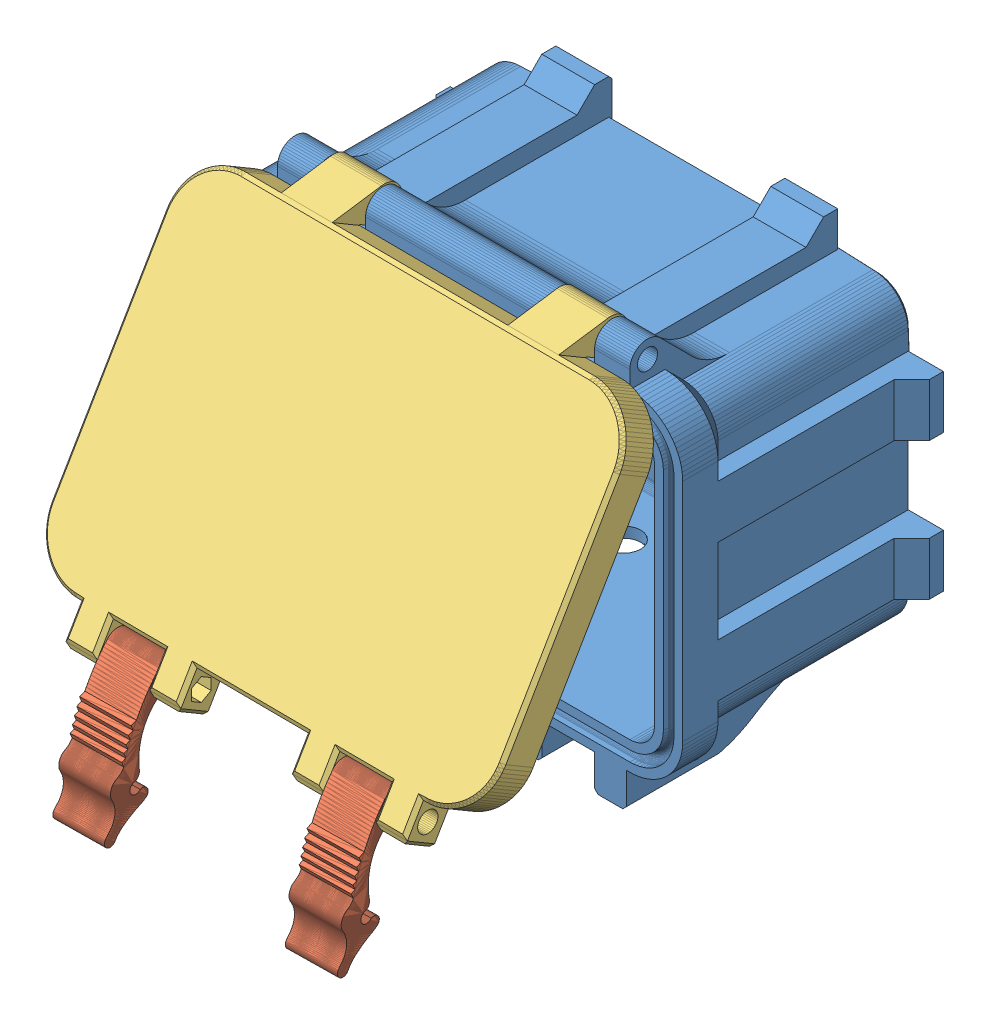
SolidWorks assembly Assem1, configuration Default. Lengths in mm.
Overall size (178.06 170.46 187.47).
4 component instances, 3 part files, 0 mates.
Components (placement in the parent):
- Enclosure-1: Enclosure [Default] at (87.724 108.5663 114.8266) size (178.06 144.98 89.03)
- Enclosure_Latch-1: Enclosure_Latch [Default] at (138.0626 22.1655 279.5419) x (-0.005073 0.943211 -0.332155) z (-0.999905 -0.000526 0.013778) size (53.78 15.23 18.57)
- LID-1: LID [Default] at (-71.5061 242.0804 171.4742) x (0.999924 0.005105 0.011251) z (0.001258 0.863849 -0.50375) size (165.36 25.43 145.01)
- Enclosure_Latch-2: Enclosure_Latch [Default] at (56.0413 22.1331 281.705) x (-0.008727 0.92047 -0.390716) z (-0.999962 -0.008033 0.00341) size (53.78 15.23 18.57)
